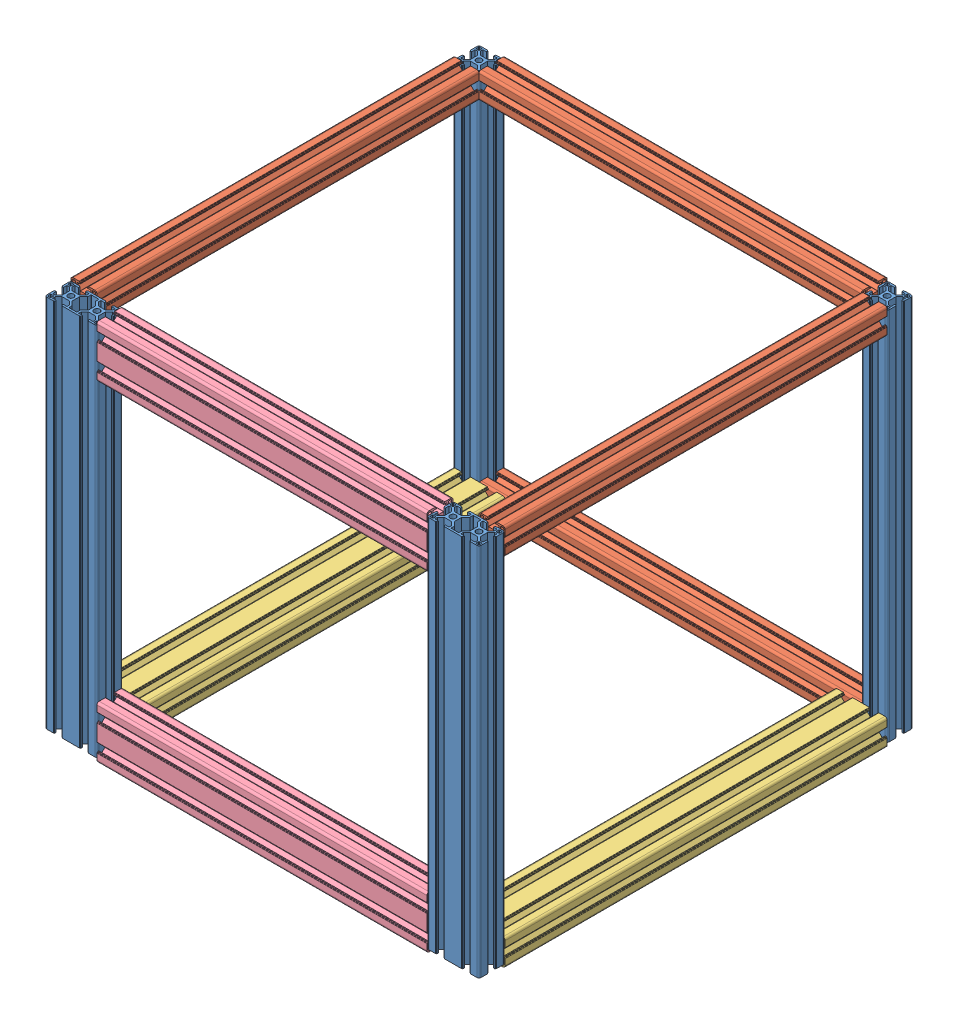
SolidWorks assembly 大箱子, configuration 默认. Lengths in mm.
Overall size (500 440 500).
9 component instances, 4 part files, 26 mates.
Components (placement in the parent):
- 框架草图-1: 框架草图 [Default<按加工>] at (11548.0415 -11088.9705 227.7336) size (500 431 500)
- 3030-440-1: 3030-440 [默认] at (-452.3693 146.7248 -220) size (30 30 440)
- 3060-440-2: 3060-440 [默认] at (-442.988 -259.1423 -220) size (60 30 440)
- 3060-380-1: 3060-380 [默认] at (95.6059 309.7008 189.7508) x (0 -1 0) z (-1 0 0) size (60 30 380)
- 3030-440-3: 3030-440 [默认] at (125.6059 146.7248 -357.9752) x (0 0 1) z (-1 0 0) size (30 30 440)
- 3030-440-4: 3030-440 [默认] at (17.6307 146.7248 -220) size (30 30 440)
- 3060-380-4: 3060-380 [默认] at (95.6059 -70.2992 189.7508) x (0 -1 0) z (-1 0 0) size (60 30 380)
- 3060-440-3: 3060-440 [默认] at (-2.988 -259.1423 -220) size (60 30 440)
- 3030-440-7: 3030-440 [默认] at (125.6059 -263.2752 -357.9752) x (0 0 1) z (-1 0 0) size (30 30 440)
Mates (geometry in assembly coordinates):
- 重合2: coincident aligned: plane of 框架草图-1 through (-304.5941 -224.3931 250) normal (0 0 1); plane of 3060-380-1 through (-284.3941 190.6069 250) normal (0 0 1)
- 重合3: coincident anti-aligned: plane of 框架草图-1 through (-284.3941 -224.3931 240.075) normal (1 0 0); plane of 3060-380-1 through (-284.3941 161.2069 249.3) normal (-1 0 0)
- 距离1: distance = 4.5 mm aligned: plane of 3060-380-1 through (-284.3941 211.1069 240.5) normal (0 1 0); plane of 框架草图-1 through (-341.8941 206.6069 247.5) normal (0 1 0)
- 重合5: coincident aligned: plane of 框架草图-1 through (-284.3941 -224.3931 240.075) normal (1 0 0); plane of 3060-440-2 through (-284.3941 -201.3931 220) normal (1 0 0)
- 重合6: coincident anti-aligned: plane of 框架草图-1 through (-324.1941 -224.3931 220) normal (0 0 -1); plane of 3060-440-2 through (-294.4941 -199.5931 220) normal (0 0 1)
- 距离2: distance = 4.5 mm aligned: plane of 框架草图-1 through (-341.8941 -224.3931 247.5) normal (0 -1 0); plane of 3060-440-2 through (-286.8941 -228.8931 220) normal (0 -1 0)
- 重合11: coincident aligned: plane of 框架草图-1 through (-304.5941 -224.3931 250) normal (0 0 1); plane of 3060-380-4 through (-284.3941 -189.3931 250) normal (0 0 1)
- 重合12: coincident anti-aligned: plane of 框架草图-1 through (-284.3941 -224.3931 240.075) normal (1 0 0); plane of 3060-380-4 through (-284.3941 -218.7931 249.3) normal (-1 0 0)
- 距离6: distance = 4.5 mm aligned: plane of 3060-380-4 through (-284.3941 -228.8931 247.5) normal (0 -1 0); plane of 框架草图-1 through (-341.8941 -224.3931 247.5) normal (0 -1 0)
- 重合18: coincident anti-aligned: plane of 框架草图-1 through (-324.1941 -224.3931 220) normal (0 0 -1); plane of 3060-440-3 through (145.5059 -199.5931 220) normal (0 0 1)
- 重合19: coincident aligned: plane of 框架草图-1 through (155.6059 -224.3931 229.925) normal (1 0 0); plane of 3060-440-3 through (155.6059 -201.3931 220) normal (1 0 0)
- 距离7: distance = 4.5 mm aligned: plane of 框架草图-1 through (-341.8941 -224.3931 247.5) normal (0 -1 0); plane of 3060-440-3 through (153.1059 -228.8931 220) normal (0 -1 0)
- 重合21: coincident anti-aligned: plane of 框架草图-1 through (145.8059 -224.3931 220) normal (0 0 -1); plane of 3030-440-4 through (136.4858 202.2069 220) normal (0 0 1)
- 重合22: coincident aligned: plane of 框架草图-1 through (155.6059 -224.3931 229.925) normal (1 0 0); plane of 3030-440-4 through (155.6059 201.6069 220) normal (1 0 0)
- 距离9: distance = 4.5 mm aligned: plane of 3030-440-4 through (153.1059 211.1069 220) normal (0 1 0); plane of 框架草图-1 through (153.1059 206.6069 222.5) normal (0 1 0)
- 重合24: coincident anti-aligned: plane of 框架草图-1 through (145.8059 -224.3931 220) normal (0 0 -1); plane of 3030-440-5 through (-325.274 211.0069 220) normal (0 0 1)
- 距离10: distance = 4.5 mm anti-aligned: plane of 3030-440-5 through (-341.8941 202.1069 220) normal (0 -1 0); plane of 框架草图-1 through (153.1059 206.6069 222.5) normal (0 1 0)
- 重合27: coincident aligned: plane of 框架草图-1 through (-344.3941 -224.3931 222.5) normal (-1 0 0); plane of 3030-440-1 through (-344.3941 208.6069 220) normal (-1 0 0)
- 重合28: coincident anti-aligned: plane of 框架草图-1 through (-341.8941 -224.3931 220) normal (0 0 -1); plane of 3030-440-1 through (-333.5142 202.2069 220) normal (0 0 1)
- 距离12: distance = 4.5 mm aligned: plane of 3030-440-1 through (-334.8941 211.1069 220) normal (0 1 0); plane of 框架草图-1 through (-341.8941 206.6069 247.5) normal (0 1 0)
- 重合30: coincident anti-aligned: plane of 框架草图-1 through (125.6059 -224.3931 -247.5) normal (-1 0 0); plane of 3030-440-3 through (125.6059 202.2069 -239.1201) normal (1 0 0)
- 重合31: coincident aligned: plane of 框架草图-1 through (128.1059 -224.3931 -250) normal (0 0 -1); plane of 3030-440-3 through (-314.3941 208.6069 -250) normal (0 0 -1)
- 距离13: distance = 4.5 mm aligned: plane of 3030-440-3 through (-314.3941 211.1069 -240.5) normal (0 1 0); plane of 框架草图-1 through (128.1059 206.6069 -222.5) normal (0 1 0)
- 重合33: coincident anti-aligned: plane of 框架草图-1 through (125.6059 -224.3931 -247.5) normal (-1 0 0); plane of 3030-440-7 through (125.6059 -207.7931 -239.1201) normal (1 0 0)
- 重合34: coincident aligned: plane of 框架草图-1 through (128.1059 -224.3931 -250) normal (0 0 -1); plane of 3030-440-7 through (-314.3941 -201.3931 -250) normal (0 0 -1)
- 距离14: distance = 4.5 mm aligned: plane of 3030-440-7 through (-314.3941 -228.8931 -229.5) normal (0 -1 0); plane of 框架草图-1 through (128.1059 -224.3931 -222.5) normal (0 -1 0)
